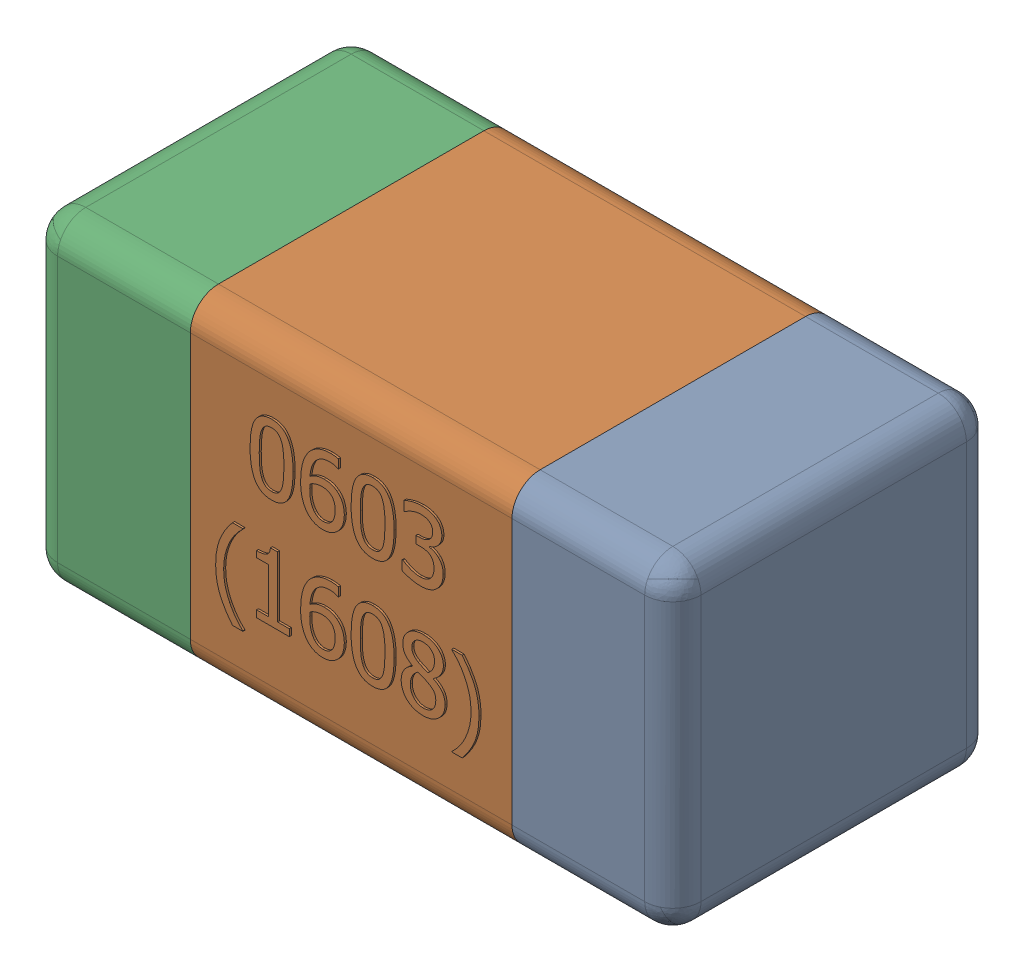
SolidWorks assembly C33, configuration Standard. Lengths in mm.
Overall size (1.61 0.81 0.81).
4 component instances, 3 part files, 0 mates.
Components (placement in the parent):
- C33-subassembly-1-1: C33-subassembly-1 [Standard] at (8.4001 -8.4999 0) x (1 0 0) z (0 0 1) size (1.61 0.81 0.81)
  - User Library-0603_Cap-1: User Library-0603_Cap [Standard] at origin size (0.41 0.81 0.81)
  - User Library-0603_Cap-1-1: User Library-0603_Cap-1 [Standard] at origin size (0.8 0.8 0.81)
  - User Library-0603_Cap-2-1: User Library-0603_Cap-2 [Standard] at origin size (0.41 0.81 0.81)
